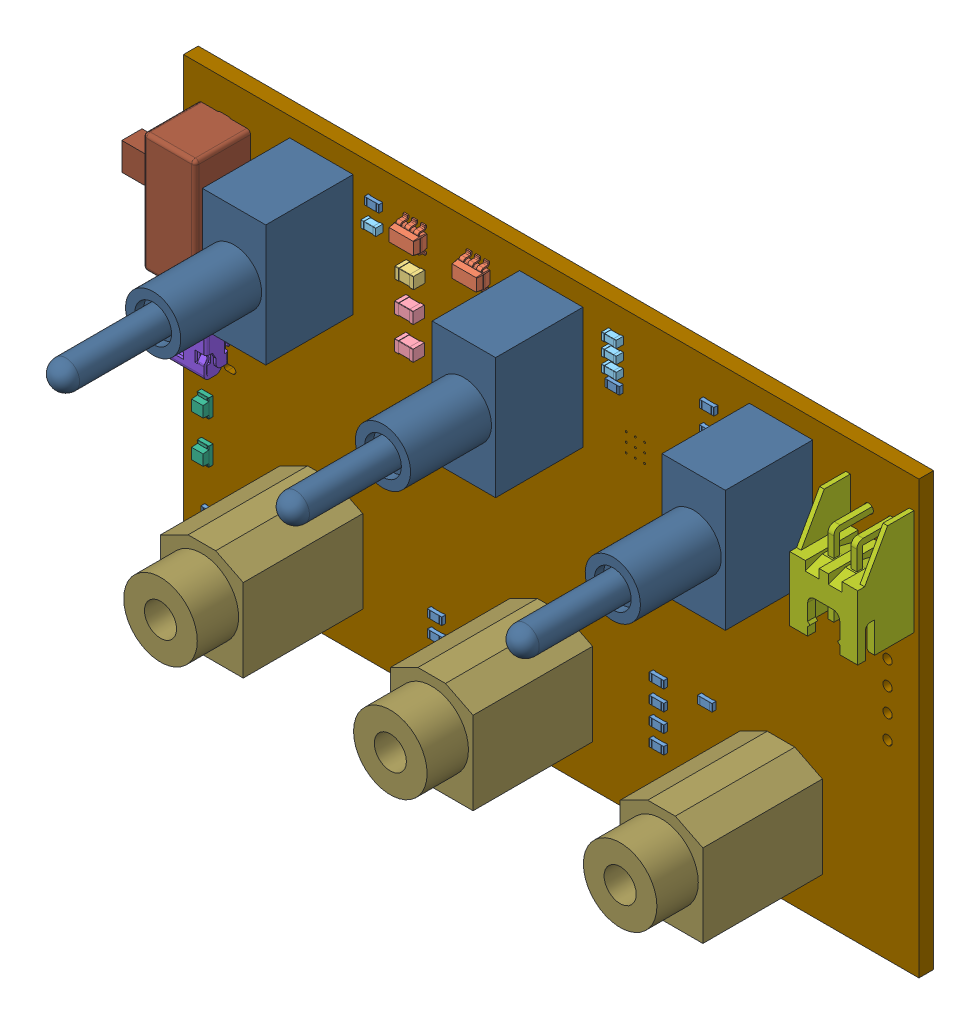
SolidWorks assembly PCB-assembly, configuration Default. Lengths in mm.
Overall size (82.41 47 33.7).
107 component instances, 22 part files, 37 mates.
Components (placement in the parent):
- ledTruck_PCB.step-1: ledTruck_PCB.step [Default] at (-218.1999 94.1524 35.3841) size (80.38 47 12.68)
  - ledTruck.step-1: ledTruck.step [Default] at origin size (80.38 47 12.68)
    - R_0603_1608Metric.step-1: R_0603_1608Metric.step [Default] at (162.2298 -104.8258 1.65) size (1.6 0.8 0.45)
      - SOLID.step-1: SOLID.step [Default] at origin size (1.6 0.8 0.45)
    - SOT-23-5.step-1: SOT-23-5.step [Default] at (130.302 -76.708 1.65) x (0 -1 0) z (0 0 1) size (2.8 2.9 1.55)
      - SOLID-0.step-1: SOLID-0.step [Default] at origin size (2.8 2.9 1.55)
    - SOT-23-5.step-2: SOT-23-5.step [Default] at (137.16 -76.708 1.65) x (0 -1 0) z (0 0 1) size (2.8 2.9 1.55)
      - SOLID-0.step-1: SOLID-0.step [Default] at origin size (2.8 2.9 1.55)
    - R_0603_1608Metric.step-2: R_0603_1608Metric.step [Default] at (162.433 -79.248 1.65) size (1.6 0.8 0.45)
      - SOLID.step-1: SOLID.step [Default] at origin size (1.6 0.8 0.45)
    - R_0603_1608Metric.step-3: R_0603_1608Metric.step [Default] at (162.433 -76.835 1.65) x (-1 0 0) z (0 0 1) size (1.6 0.8 0.45)
      - SOLID.step-1: SOLID.step [Default] at origin size (1.6 0.8 0.45)
    - R_0603_1608Metric.step-4: R_0603_1608Metric.step [Default] at (108.1929 -114.012 1.65) size (1.6 0.8 0.45)
      - SOLID.step-1: SOLID.step [Default] at origin size (1.6 0.8 0.45)
    - R_0603_1608Metric.step-5: R_0603_1608Metric.step [Default] at (108.1929 -115.512 1.65) size (1.6 0.8 0.45)
      - SOLID.step-1: SOLID.step [Default] at origin size (1.6 0.8 0.45)
    - R_0603_1608Metric.step-6: R_0603_1608Metric.step [Default] at (152.146 -80.01 1.65) size (1.6 0.8 0.45)
      - SOLID.step-1: SOLID.step [Default] at origin size (1.6 0.8 0.45)
    - R_0603_1608Metric.step-7: R_0603_1608Metric.step [Default] at (165.1 -84.836 1.65) x (0 1 0) z (0 0 1) size (1.6 0.8 0.45)
      - SOLID.step-1: SOLID.step [Default] at origin size (1.6 0.8 0.45)
    - R_0603_1608Metric.step-8: R_0603_1608Metric.step [Default] at (137.16 -80.264 1.65) x (-1 0 0) z (0 0 1) size (1.6 0.8 0.45)
      - SOLID.step-1: SOLID.step [Default] at origin size (1.6 0.8 0.45)
    - R_0603_1608Metric.step-9: R_0603_1608Metric.step [Default] at (156.972 -111.506 1.65) x (-1 0 0) z (0 0 1) size (1.6 0.8 0.45)
      - SOLID.step-1: SOLID.step [Default] at origin size (1.6 0.8 0.45)
    - R_0603_1608Metric.step-10: R_0603_1608Metric.step [Default] at (156.972 -107.442 1.65) size (1.6 0.8 0.45)
      - SOLID.step-1: SOLID.step [Default] at origin size (1.6 0.8 0.45)
    - R_0603_1608Metric.step-11: R_0603_1608Metric.step [Default] at (132.842 -113.284 1.65) size (1.6 0.8 0.45)
      - SOLID.step-1: SOLID.step [Default] at origin size (1.6 0.8 0.45)
    - R_0603_1608Metric.step-12: R_0603_1608Metric.step [Default] at (156.972 -109.474 1.65) x (-1 0 0) z (0 0 1) size (1.6 0.8 0.45)
      - SOLID.step-1: SOLID.step [Default] at origin size (1.6 0.8 0.45)
    - R_0603_1608Metric.step-13: R_0603_1608Metric.step [Default] at (156.972 -105.283 1.65) x (-1 0 0) z (0 0 1) size (1.6 0.8 0.45)
      - SOLID.step-1: SOLID.step [Default] at origin size (1.6 0.8 0.45)
    - R_0603_1608Metric.step-14: R_0603_1608Metric.step [Default] at (132.828 -111.379 1.65) size (1.6 0.8 0.45)
      - SOLID.step-1: SOLID.step [Default] at origin size (1.6 0.8 0.45)
    - L_0805_2012Metric.step-1: L_0805_2012Metric.step [Default] at (130.336 -80.264 1.65) x (-1 0 0) z (0 0 1) size (2 1.25 1.25)
      - SOLID-1.step-1: SOLID-1.step [Default] at origin size (2 1.25 1.25)
    - C_0805_2012Metric.step-1: C_0805_2012Metric.step [Default] at (130.302 -87.122 1.65) size (2 1.25 1.25)
      - SOLID-2.step-1: SOLID-2.step [Default] at origin size (2 1.25 1.25)
    - C_0603_1608Metric.step-1: C_0603_1608Metric.step [Default] at (152.146 -78.486 1.65) x (-1 0 0) z (0 0 1) size (1.6 0.8 0.8)
      - SOLID-3.step-1: SOLID-3.step [Default] at origin size (1.6 0.8 0.8)
    - C_0805_2012Metric.step-2: C_0805_2012Metric.step [Default] at (137.16 -83.566 1.65) size (2 1.25 1.25)
      - SOLID-2.step-1: SOLID-2.step [Default] at origin size (2 1.25 1.25)
    - C_0603_1608Metric.step-2: C_0603_1608Metric.step [Default] at (152.146 -76.962 1.65) x (-1 0 0) z (0 0 1) size (1.6 0.8 0.8)
      - SOLID-3.step-1: SOLID-3.step [Default] at origin size (1.6 0.8 0.8)
    - C_0603_1608Metric.step-3: C_0603_1608Metric.step [Default] at (152.146 -75.464 1.65) x (-1 0 0) z (0 0 1) size (1.6 0.8 0.8)
      - SOLID-3.step-1: SOLID-3.step [Default] at origin size (1.6 0.8 0.8)
    - C_0805_2012Metric.step-3: C_0805_2012Metric.step [Default] at (130.302 -83.566 1.65) size (2 1.25 1.25)
      - SOLID-2.step-1: SOLID-2.step [Default] at origin size (2 1.25 1.25)
    - C_0603_1608Metric.step-4: C_0603_1608Metric.step [Default] at (162.56 -81.534 1.65) size (1.6 0.8 0.8)
      - SOLID-3.step-1: SOLID-3.step [Default] at origin size (1.6 0.8 0.8)
    - C_0603_1608Metric.step-5: C_0603_1608Metric.step [Default] at (162.56 -88.138 1.65) size (1.6 0.8 0.8)
      - SOLID-3.step-1: SOLID-3.step [Default] at origin size (1.6 0.8 0.8)
    - C_0805_2012Metric.step-4: C_0805_2012Metric.step [Default] at (137.16 -87.122 1.65) size (2 1.25 1.25)
      - SOLID-2.step-1: SOLID-2.step [Default] at origin size (2 1.25 1.25)
    - R_0603_1608Metric.step-15: R_0603_1608Metric.step [Default] at (125.984 -75.946 1.65) size (1.6 0.8 0.45)
      - SOLID.step-1: SOLID.step [Default] at origin size (1.6 0.8 0.45)
    - R_0603_1608Metric.step-16: R_0603_1608Metric.step [Default] at (114.046 -80.264 1.65) x (0 -1 0) z (0 0 1) size (1.6 0.8 0.45)
      - SOLID.step-1: SOLID.step [Default] at origin size (1.6 0.8 0.45)
    - LED_0805_2012Metric.step-1: LED_0805_2012Metric.step [Default] at (107.6929 -108.512 1.65) x (0 -1 0) z (0 0 1) size (2 1.25 1.1)
      - SOLID-4.step-1: SOLID-4.step [Default] at origin size (2 1.25 1.1)
    - LED_0805_2012Metric.step-2: LED_0805_2012Metric.step [Default] at (107.6929 -103.962 1.65) x (0 -1 0) z (0 0 1) size (2 1.25 1.1)
      - SOLID-4.step-1: SOLID-4.step [Default] at origin size (2 1.25 1.1)
    - C_0603_1608Metric.step-6: C_0603_1608Metric.step [Default] at (125.984 -77.978 1.65) x (-1 0 0) z (0 0 1) size (1.6 0.8 0.8)
      - SOLID-3.step-1: SOLID-3.step [Default] at origin size (1.6 0.8 0.8)
    - SW_CuK_JS202011AQN_DPDT_Angled.step-1: SW_CuK_JS202011AQN_DPDT_Angled.step [Default] at (111.474 -79.012 1.65) x (0 -1 0) z (0 0 1) size (9 5.6 6.5) (hidden)
      - SOLID-5.step-1: SOLID-5.step [Default] at origin size (9 5.6 6.5)
    - JST_XH_S2B-XH-A_1x02_P2.50mm_Horizontal.step-1: JST_XH_S2B-XH-A_1x02_P2.50mm_Horizontal.step [Default] at (179.578 -78.012 1.65) size (7.4 11.5 9.5)
      - SOLID-6.step-1: SOLID-6.step [Default] at origin size (7.4 11.5 9.5)
    - USB_Micro-B_Molex_47346-0001.step-1: USB_Micro-B_Molex_47346-0001.step [Default] at (108.4213 -96.0044 1.65) x (0 -1 0) z (0 0 1) size (7.98 5.42 2.94)
      - SOLID-7.step-1: SOLID-7.step [Default] at origin size (7.98 5.42 2.94)
    - Crystal_SMD_0603-4Pin_6.0x3.5mm.step-1: Crystal_SMD_0603-4Pin_6.0x3.5mm.step [Default] at (162.56 -84.856 1.65) x (0 1 0) z (0 0 1) size (6 3.5 1.03)
      - SOLID-8.step-1: SOLID-8.step [Default] at origin size (6 3.5 1.03) (hidden)
    - 7101 ToggleSwitch.step-1: 7101 ToggleSwitch.step [Default] at (121.534 -82.012 10.15) size (0.36 0.5 1.28) (hidden)
      - SOLID-9.step-1: SOLID-9.step [Default] at origin size (0.28 0.5 0.35) (hidden)
      - SOLID-10.step-1: SOLID-10.step [Default] at origin size (0.24 0.24 0.35)
      - SOLID-11.step-1: SOLID-11.step [Default] at origin size (0.12 0.21 0.43)
      - SOLID-12.step-1: SOLID-12.step [Default] at origin size (0.36 0.31 0.06)
      - SOLID-13.step-1: SOLID-13.step [Default] at origin size (0.36 0.31 0.06)
      - SOLID-14.step-1: SOLID-14.step [Default] at origin size (0.08 0.03 0.16)
      - SOLID-15.step-1: SOLID-15.step [Default] at origin size (0.08 0.03 0.16)
      - SOLID-16.step-1: SOLID-16.step [Default] at origin size (0.08 0.03 0.16)
    - 7101 ToggleSwitch.step-2: 7101 ToggleSwitch.step [Default] at (146.534 -82.012 10.15) size (0.36 0.5 1.28) (hidden)
      - SOLID-9.step-1: SOLID-9.step [Default] at origin size (0.28 0.5 0.35) (hidden)
      - SOLID-10.step-1: SOLID-10.step [Default] at origin size (0.24 0.24 0.35)
      - SOLID-11.step-1: SOLID-11.step [Default] at origin size (0.12 0.21 0.43)
      - SOLID-12.step-1: SOLID-12.step [Default] at origin size (0.36 0.31 0.06)
      - SOLID-13.step-1: SOLID-13.step [Default] at origin size (0.36 0.31 0.06)
      - SOLID-14.step-1: SOLID-14.step [Default] at origin size (0.08 0.03 0.16)
      - SOLID-15.step-1: SOLID-15.step [Default] at origin size (0.08 0.03 0.16)
      - SOLID-16.step-1: SOLID-16.step [Default] at origin size (0.08 0.03 0.16)
    - 7101 ToggleSwitch.step-3: 7101 ToggleSwitch.step [Default] at (171.534 -82.012 10.15) size (0.36 0.5 1.28) (hidden)
      - SOLID-9.step-1: SOLID-9.step [Default] at origin size (0.28 0.5 0.35) (hidden)
      - SOLID-10.step-1: SOLID-10.step [Default] at origin size (0.24 0.24 0.35)
      - SOLID-11.step-1: SOLID-11.step [Default] at origin size (0.12 0.21 0.43)
      - SOLID-12.step-1: SOLID-12.step [Default] at origin size (0.36 0.31 0.06)
      - SOLID-13.step-1: SOLID-13.step [Default] at origin size (0.36 0.31 0.06)
      - SOLID-14.step-1: SOLID-14.step [Default] at origin size (0.08 0.03 0.16)
      - SOLID-15.step-1: SOLID-15.step [Default] at origin size (0.08 0.03 0.16)
      - SOLID-16.step-1: SOLID-16.step [Default] at origin size (0.08 0.03 0.16)
    - COMPOUND.step-1: COMPOUND.step [Default] at origin size (80 47 1.6)
- toggle-switch-2: toggle-switch [Default] at (-47.8013 13.9041 36.9841) x (1 0 0) z (0 -1 0) size (6.9 31.5 13.2)
- toggle-switch-3: toggle-switch [Default] at (-72.8013 13.9041 36.9841) x (1 0 0) z (0 -1 0) size (6.9 31.5 13.2)
- toggle-switch-4: toggle-switch [Default] at (-97.8013 13.9041 36.9841) x (1 0 0) z (0 -1 0) size (6.9 31.5 13.2)
- slideswitch-1: slideswitch [Default] at (-109.6165 12.0841 36.9841) x (0 -1 0) z (-1 0 0) size (13 8.2 9.7)
- 3,5mmjack_MultiComp-1: 3,5mmjack_MultiComp [Default] at (-97.9637 -15.2725 36.9841) size (9 10.5 21.9)
- 3,5mmjack_MultiComp-4: 3,5mmjack_MultiComp [Default] at (-72.9637 -15.2725 36.9841) size (9 10.5 21.9)
- 3,5mmjack_MultiComp-5: 3,5mmjack_MultiComp [Default] at (-47.9637 -15.2725 36.9841) size (9 10.5 21.9)
Mates (geometry in assembly coordinates):
- Coincident1: coincident anti-aligned: plane of ledTruck_PCB.step-1/ledTruck.step-1/COMPOUND.step-1 through (-73.1659 -1.8596 36.9841) normal (0 0 1); plane of 3,5mmjack-1 through (-98.1659 -15.3596 36.9841) normal (0 0 -1)
- Coincident2: coincident anti-aligned: plane of ledTruck_PCB.step-1/ledTruck.step-1/COMPOUND.step-1 through (-100.2659 -16.2596 35.3841) normal (-1 0 0); plane of 3,5mmjack-1 through (-100.2659 -14.4596 34.9841) normal (1 0 0)
- Coincident3: coincident anti-aligned: plane of ledTruck_PCB.step-1/ledTruck.step-1/COMPOUND.step-1 through (-99.0659 -13.2596 35.3841) normal (0 1 0); plane of 3,5mmjack-1 through (-97.2659 -13.2596 34.9841) normal (0 -1 0)
- Coincident4: coincident anti-aligned: plane of ledTruck_PCB.step-1/ledTruck.step-1/COMPOUND.step-1 through (-73.1659 -1.8596 36.9841) normal (0 0 1); plane of 3,5mmjack-2 through (-73.1659 -15.3596 36.9841) normal (0 0 -1)
- Coincident5: coincident anti-aligned: plane of ledTruck_PCB.step-1/ledTruck.step-1/COMPOUND.step-1 through (-75.2659 -16.2596 35.3841) normal (-1 0 0); plane of 3,5mmjack-2 through (-75.2659 -14.4596 34.9841) normal (1 0 0)
- Coincident6: coincident anti-aligned: plane of ledTruck_PCB.step-1/ledTruck.step-1/COMPOUND.step-1 through (-73.1659 -1.8596 36.9841) normal (0 0 1); plane of 3,5mmjack-3 through (-48.1659 -15.3596 36.9841) normal (0 0 -1)
- Coincident7: coincident anti-aligned: plane of ledTruck_PCB.step-1/ledTruck.step-1/COMPOUND.step-1 through (-50.2659 -16.2596 35.3841) normal (-1 0 0); plane of 3,5mmjack-3 through (-50.2659 -14.4596 34.9841) normal (1 0 0)
- Coincident8: coincident anti-aligned: plane of ledTruck_PCB.step-1/ledTruck.step-1/COMPOUND.step-1 through (-49.0659 -13.2596 35.3841) normal (0 1 0); plane of 3,5mmjack-3 through (-47.2659 -13.2596 34.9841) normal (0 -1 0)
- Coincident12: coincident anti-aligned: plane of ledTruck_PCB.step-1/ledTruck.step-1/COMPOUND.step-1 through (-74.0659 -13.2596 35.3841) normal (0 1 0); plane of 3,5mmjack-2 through (-72.2659 -13.2596 34.9841) normal (0 -1 0)
- Coincident13: coincident anti-aligned: plane of ledTruck_PCB.step-1/ledTruck.step-1/COMPOUND.step-1 through (-73.1659 -1.8596 36.9841) normal (0 0 1); plane of toggle-switch-2 through (-47.8013 13.9041 36.9841) normal (0 0 -1)
- Coincident14: coincident anti-aligned: plane of ledTruck_PCB.step-1/ledTruck.step-1/COMPOUND.step-1 through (-47.5659 8.7904 35.3841) normal (0 -1 0); plane of toggle-switch-2 through (-48.7659 8.7904 34.7841) normal (0 1 0)
- Concentric5: concentric anti-aligned: cylinder of ledTruck_PCB.step-1/ledTruck.step-1/COMPOUND.step-1 through (-47.5659 8.1404 35.3841) axis (0 0 -1) radius 0.65; cylinder of toggle-switch-2 through (-47.5659 8.1404 34.7841) axis (0 0 1) radius 0.65
- Coincident17: coincident anti-aligned: plane of ledTruck_PCB.step-1/ledTruck.step-1/COMPOUND.step-1 through (-73.1659 -1.8596 36.9841) normal (0 0 1); plane of toggle-switch-3 through (-72.8013 13.9041 36.9841) normal (0 0 -1)
- Coincident18: coincident anti-aligned: plane of ledTruck_PCB.step-1/ledTruck.step-1/COMPOUND.step-1 through (-72.5659 8.7904 35.3841) normal (0 -1 0); plane of toggle-switch-3 through (-73.7659 8.7904 34.7841) normal (0 1 0)
- Concentric6: concentric anti-aligned: cylinder of ledTruck_PCB.step-1/ledTruck.step-1/COMPOUND.step-1 through (-72.5659 8.1404 35.3841) axis (0 0 -1) radius 0.65; cylinder of toggle-switch-3 through (-72.5659 8.1404 34.7841) axis (0 0 1) radius 0.65
- Coincident19: coincident anti-aligned: plane of ledTruck_PCB.step-1/ledTruck.step-1/COMPOUND.step-1 through (-73.1659 -1.8596 36.9841) normal (0 0 1); plane of toggle-switch-4 through (-97.8013 13.9041 36.9841) normal (0 0 -1)
- Coincident20: coincident anti-aligned: plane of ledTruck_PCB.step-1/ledTruck.step-1/COMPOUND.step-1 through (-97.5659 8.7904 35.3841) normal (0 -1 0); plane of toggle-switch-4 through (-98.7659 8.7904 34.7841) normal (0 1 0)
- Concentric7: concentric anti-aligned: cylinder of ledTruck_PCB.step-1/ledTruck.step-1/COMPOUND.step-1 through (-97.5659 8.1404 35.3841) axis (0 0 -1) radius 0.65; cylinder of toggle-switch-4 through (-97.5659 8.1404 34.7841) axis (0 0 1) radius 0.65
- Coincident22: coincident anti-aligned: plane of ledTruck_PCB.step-1/ledTruck.step-1/COMPOUND.step-1 through (-73.1659 -1.8596 36.9841) normal (0 0 1); plane of slideswitch-1 through (-109.6165 12.0841 36.9841) normal (0 0 -1)
- Concentric8: concentric aligned: cylinder of ledTruck_PCB.step-1/ledTruck.step-1/COMPOUND.step-1 through (-108.7259 14.6404 34.5841) axis (0 0 1) radius 0.5; cylinder of slideswitch-1 through (-108.7259 14.6404 34.7841) axis (0 0 1) radius 0.4
- Concentric9: concentric aligned: cylinder of ledTruck_PCB.step-1/ledTruck.step-1/COMPOUND.step-1 through (-108.7259 11.6404 34.5841) axis (0 0 1) radius 0.5; cylinder of slideswitch-1 through (-108.7259 11.6404 34.7841) axis (0 0 1) radius 0.4
- Coincident23: coincident anti-aligned: plane of ledTruck_PCB.step-1/ledTruck.step-1/COMPOUND.step-1 through (-73.1659 -1.8596 36.9841) normal (0 0 1); plane of 3,5mmjack_MultiComp-1 through (-97.9637 -15.2725 36.9841) normal (0 0 -1)
- Distance1: distance = 15 mm: cylinder of 3,5mmjack_MultiComp-1 through (-98.1659 -15.3596 39.9841) axis (0 0 1) radius 1.75; plane of ledTruck_PCB.step-1/ledTruck.step-1/COMPOUND.step-1 through (-113.1659 -25.3596 35.3841) normal (-1 0 0)
- Distance2: distance = 10 mm: cylinder of 3,5mmjack_MultiComp-1 through (-98.1659 -15.3596 39.9841) axis (0 0 1) radius 1.75; plane of ledTruck_PCB.step-1/ledTruck.step-1/COMPOUND.step-1 through (-33.1659 -25.3596 35.3841) normal (0 -1 0)
- Parallel1: parallel aligned: plane of ledTruck_PCB.step-1/ledTruck.step-1/COMPOUND.step-1 through (-33.1659 -25.3596 35.3841) normal (0 -1 0); plane of 3,5mmjack_MultiComp-1 through (-102.6659 -20.8596 49.9841) normal (0 -1 0)
- Coincident25: coincident anti-aligned: plane of ledTruck_PCB.step-1/ledTruck.step-1/COMPOUND.step-1 through (-73.1659 -1.8596 36.9841) normal (0 0 1); plane of 3,5mmjack_MultiComp-4 through (-72.9637 -15.2725 36.9841) normal (0 0 -1)
- Distance6: distance = 40 mm: cylinder of 3,5mmjack_MultiComp-4 through (-73.1659 -15.3596 39.9841) axis (0 0 1) radius 1.75; plane of ledTruck_PCB.step-1/ledTruck.step-1/COMPOUND.step-1 through (-113.1659 -25.3596 35.3841) normal (-1 0 0)
- Distance7: distance = 10 mm: cylinder of 3,5mmjack_MultiComp-4 through (-73.1659 -15.3596 39.9841) axis (0 0 1) radius 1.75; plane of ledTruck_PCB.step-1/ledTruck.step-1/COMPOUND.step-1 through (-33.1659 -25.3596 35.3841) normal (0 -1 0)
- Parallel2: parallel aligned: plane of ledTruck_PCB.step-1/ledTruck.step-1/COMPOUND.step-1 through (-33.1659 -25.3596 35.3841) normal (0 -1 0); plane of 3,5mmjack_MultiComp-4 through (-77.6659 -20.8596 49.9841) normal (0 -1 0)
- Coincident26: coincident anti-aligned: plane of ledTruck_PCB.step-1/ledTruck.step-1/COMPOUND.step-1 through (-73.1659 -1.8596 36.9841) normal (0 0 1); plane of 3,5mmjack_MultiComp-5 through (-47.9637 -15.2725 36.9841) normal (0 0 -1)
- Distance8: distance = 65 mm: cylinder of 3,5mmjack_MultiComp-5 through (-48.1659 -15.3596 39.9841) axis (0 0 1) radius 1.75; plane of ledTruck_PCB.step-1/ledTruck.step-1/COMPOUND.step-1 through (-113.1659 -25.3596 35.3841) normal (-1 0 0)
- Distance9: distance = 10 mm: cylinder of 3,5mmjack_MultiComp-5 through (-48.1659 -15.3596 39.9841) axis (0 0 1) radius 1.75; plane of ledTruck_PCB.step-1/ledTruck.step-1/COMPOUND.step-1 through (-33.1659 -25.3596 35.3841) normal (0 -1 0)
- Parallel3: parallel aligned: plane of ledTruck_PCB.step-1/ledTruck.step-1/COMPOUND.step-1 through (-33.1659 -25.3596 35.3841) normal (0 -1 0); plane of 3,5mmjack_MultiComp-5 through (-52.6659 -20.8596 49.9841) normal (0 -1 0)
- Coincident27: coincident anti-aligned: plane of ledTruck_PCB.step-1/ledTruck.step-1/COMPOUND.step-1 through (-73.1659 -1.8596 36.9841) normal (0 0 1); plane of 3,5mmjack_MultiComp-6 through (-47.9637 -15.2725 36.9841) normal (0 0 -1)
- Distance10: distance = 65 mm: cylinder of 3,5mmjack_MultiComp-6 through (-48.1659 -15.3596 39.9841) axis (0 0 1) radius 1.75; plane of ledTruck_PCB.step-1/ledTruck.step-1/COMPOUND.step-1 through (-113.1659 -25.3596 35.3841) normal (-1 0 0)
- Distance11: distance = 10 mm: cylinder of 3,5mmjack_MultiComp-6 through (-48.1659 -15.3596 39.9841) axis (0 0 1) radius 1.75; plane of ledTruck_PCB.step-1/ledTruck.step-1/COMPOUND.step-1 through (-33.1659 -25.3596 35.3841) normal (0 -1 0)
- Parallel4: parallel aligned: plane of ledTruck_PCB.step-1/ledTruck.step-1/COMPOUND.step-1 through (-33.1659 -25.3596 35.3841) normal (0 -1 0); plane of 3,5mmjack_MultiComp-6 through (-52.6659 -20.8596 49.9841) normal (0 -1 0)
